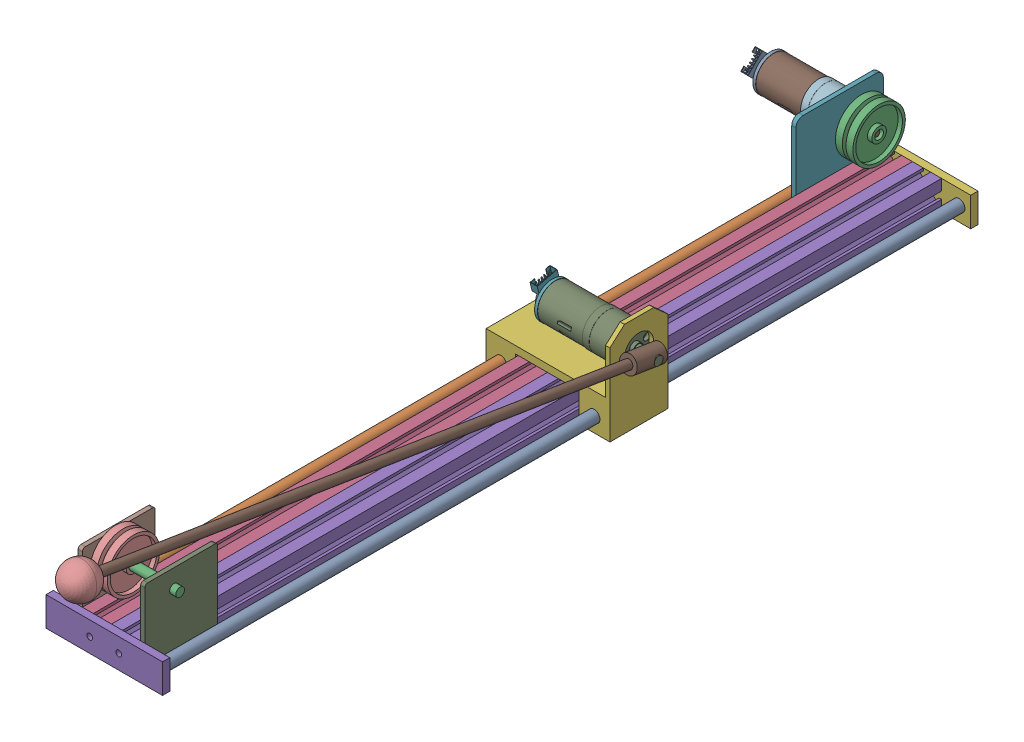
SolidWorks assembly Furuta 4 piezas, configuration Predeterminado. Lengths in mm.
Overall size (150.33 124.36 641.34).
4 component instances, 4 part files, 9 mates.
Components (placement in the parent):
- Base fija-1: Base fija [Predeterminado] at (40 0 -555) size (124.8 65 560)
- carro movil-1: carro movil [Predeterminado] at (-22.0978 0 -304.3386) size (98.5 65 40)
- masa pendulo furuta-1: masa pendulo furuta [Predeterminado] at (70.4022 105.7266 55.842) x (-0.932888 -0.355659 0.05681) z (-0.360168 0.92121 -0.147146) size (23.4 23.01 23.4)
- Pendulo-1: Pendulo [Predeterminado] at (70.4022 106.9885 63.7418) x (0 -0.987482 0.157732) z (1 0 0) size (12 399 12)
Mates (geometry in assembly coordinates):
- Coincidente1: coincident anti-aligned: plane of Base fija-1 through (0 12.5 -555) normal (-1 0 0)
- Coincidente2: coincident aligned: plane of Base fija-1 through (-20 0 0) normal (0 0 1)
- Coincidente3: coincident anti-aligned: plane of Base fija-1 through (0 0 -555) normal (0 -1 0)
- Concéntrica1: concentric aligned: cylinder of Base fija-1 through (52 10 -557.1) axis (0 0 1) radius 4; cylinder of carro movil-1 through (52 10 -344.3386) axis (0 0 1) radius 4.05
- Concéntrica2: concentric aligned: cylinder of Base fija-1 through (-12 10 -557.1) axis (0 0 1) radius 4; cylinder of carro movil-1 through (-12 10 -344.3386) axis (0 0 1) radius 4.05
- Concéntrica3: concentric anti-aligned: cylinder of carro movil-1 through (84.8875 45 -324.3386) axis (-1 0 0) radius 3; cylinder of Pendulo-1 through (60.4022 45 -324.3386) axis (1 0 0) radius 3
- Tangente1: tangent aligned: plane of carro movil-1 through (76.4022 45 -324.3386) normal (1 0 0); cylinder of Pendulo-1 through (70.4022 47.366 -309.5264) axis (0 -0.157732 -0.987482) radius 6
- Concéntrica4: concentric anti-aligned: cylinder of masa pendulo furuta-1 through (70.4022 106.9885 63.7418) axis (0 -0.157732 -0.987482) radius 3; cylinder of Pendulo-1 through (70.4022 45.4732 -321.3761) axis (0 0.157732 0.987482) radius 3
- Coincidente4: coincident anti-aligned: plane of masa pendulo furuta-1 through (70.4022 106.9885 63.7418) normal (0 -0.157732 -0.987482); plane of Pendulo-1 through (70.4022 106.9885 63.7418) normal (0 0.157732 0.987482)
